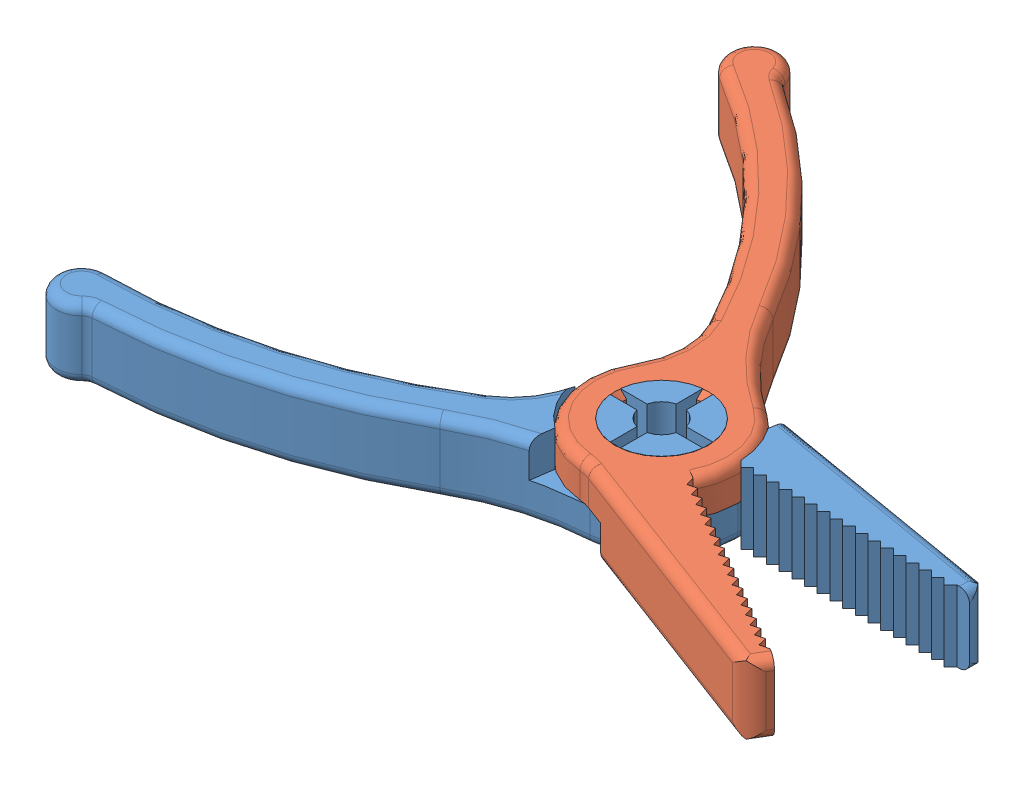
SolidWorks assembly Full Assem, configuration Default. Lengths in mm.
Overall size (99.41 9.34 76.26).
2 component instances, 2 part files, 2 mates.
Components (placement in the parent):
- Pliers Left-1: Pliers Left [Default] at (-3.5992 9.0586 -71.4637) size (92.08 9.11 34.38)
- Pliers Right-1: Pliers Right [Default] at (-44.5918 17.8978 79.3399) x (0.862388 0 0.506249) z (0.506249 0 -0.862388) size (92.08 9.18 34.38)
Mates (geometry in assembly coordinates):
- Concentric1: concentric: cylinder of Pliers Left-1 through (-28.9992 17.9232 2.6051) axis (0 -1 0) radius 5.0673; cylinder of Pliers Right-1 through (-28.9992 9.0078 2.6051) axis (0 1 0) radius 5.08
- Coincident2: coincident anti-aligned: circle of Pliers Left-1; circle of Pliers Right-1
